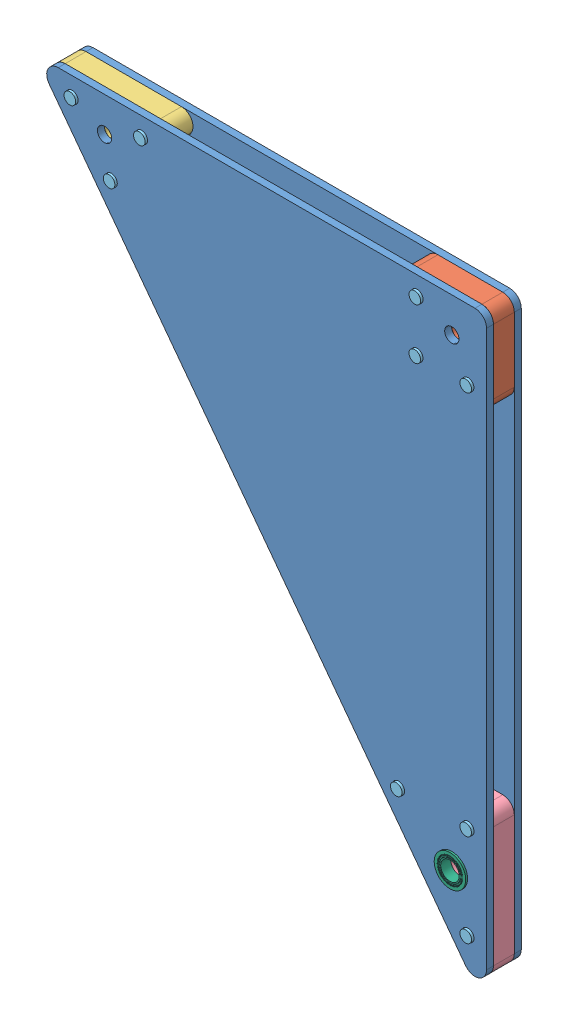
SolidWorks assembly 上方三脚架装配, configuration 默认. Lengths in mm.
Overall size (190 250 18.2).
16 component instances, 6 part files, 34 mates.
Components (placement in the parent):
- 上方三角架-1: 上方三角架 [默认] at (15.576 92.6021 249) size (190 250 3)
- 上方三角架打印连接件1-1: 上方三角架打印连接件1 [默认] at (9.4062 87.7623 261) x (-1 0 0) z (0 0 -1) size (38 38 9)
- 上方三角架打印连接件2-1: 上方三角架打印连接件2 [默认] at (-158.621 80.2816 261) x (-1 0 0) z (0 0 -1) size (51.2 41.04 9)
- 上方三角架打印连接件3-1: 上方三角架打印连接件3 [默认] at (10.8476 -100.5584 261) x (-1 0 0) z (0 0 -1) size (49 62 9)
- 上方三角架-2: 上方三角架 [默认] at (15.576 92.6021 261) size (190 250 3)
- flat head rivets gb-1: flat head rivets gb [GB_CONNECTING_PIECE_RIVET_FHRS 5X16] at (0.576 99.6021 246.8) x (0 0 1) z (-1 0 0) size (18.2 10.29 10.29)
- flat head rivets gb-2: flat head rivets gb [GB_CONNECTING_PIECE_RIVET_FHRS 5X16] at (0.576 77.6021 246.8) x (0 0 1) z (-0.08667 -0.996237 0) size (18.2 10.29 10.29)
- flat head rivets gb-3: flat head rivets gb [GB_CONNECTING_PIECE_RIVET_FHRS 5X16] at (22.576 77.6021 246.8) x (0 0 1) z (-0.981467 0.191632 0) size (18.2 10.29 10.29)
- flat head rivets gb-4: flat head rivets gb [GB_CONNECTING_PIECE_RIVET_FHRS 5X16] at (-118.424 99.6021 246.8) x (0 0 1) z (0.923728 0.383049 0) size (18.2 10.29 10.29)
- flat head rivets gb-5: flat head rivets gb [GB_CONNECTING_PIECE_RIVET_FHRS 5X16] at (-148.424 99.6021 246.8) x (0 0 1) z (0.923728 0.383049 0) size (18.2 10.29 10.29)
- flat head rivets gb-6: flat head rivets gb [GB_CONNECTING_PIECE_RIVET_FHRS 5X16] at (-131.4729 77.0007 246.8) x (0 0 1) z (-0.923728 -0.383049 0) size (18.2 10.29 10.29)
- flat head rivets gb-7: flat head rivets gb [GB_CONNECTING_PIECE_RIVET_FHRS 5X16] at (-7.424 -88.3979 246.8) x (0 0 1) z (0.923728 0.383049 0) size (18.2 10.29 10.29)
- flat head rivets gb-8: flat head rivets gb [GB_CONNECTING_PIECE_RIVET_FHRS 5X16] at (22.576 -88.3979 246.8) x (0 0 1) z (-0.990291 -0.139007 0) size (18.2 10.29 10.29)
- flat head rivets gb-9: flat head rivets gb [GB_CONNECTING_PIECE_RIVET_FHRS 5X16] at (22.576 -128.3979 246.8) x (0 0 1) z (-0.99385 -0.110732 0) size (18.2 10.29 10.29)
- SFL678ZZ深沟球法兰杯轴承-1: SFL678ZZ深沟球法兰杯轴承 [默认] at (15.576 -107.3979 262.6) x (0 0 1) z (-0.7065 0.707713 0) size (4.3 13.6 13.6)
- SFL678ZZ深沟球法兰杯轴承-2: SFL678ZZ深沟球法兰杯轴承 [默认] at (15.576 -107.3979 250.4) x (0 0 -1) z (0.871739 0.48997 0) size (4.3 13.6 13.6)
Mates (geometry in assembly coordinates):
- 同心1: concentric: cylinder of 上方三角架-1 through (15.576 -107.3979 252) axis (0 0 -1) radius 6.05; cylinder of 上方三角架打印连接件3-1 through (15.576 -107.3979 252) axis (0 0 1) radius 6
- 重合1: coincident: cylinder of 上方三角架-1 through (-7.424 -88.3979 252) axis (0 0 -1) radius 2.6; circle of 上方三角架打印连接件3-1
- 重合2: coincident: plane of 上方三角架-1 through (15.576 92.6021 252) normal (0 0 1); plane of 上方三角架打印连接件3-1 through (10.8476 -100.5584 252) normal (0 0 -1)
- 同心2: concentric: cylinder of 上方三角架-1 through (15.576 92.6021 252) axis (0 0 -1) radius 3.1; cylinder of 上方三角架打印连接件1-1 through (15.576 92.6021 252) axis (0 0 1) radius 3.05
- 重合3: coincident: plane of 上方三角架-1 through (15.576 92.6021 252) normal (0 0 1); plane of 上方三角架打印连接件1-1 through (9.4062 87.7623 252) normal (0 0 -1)
- 同心3: concentric: cylinder of 上方三角架-1 through (22.576 77.6021 252) axis (0 0 -1) radius 2.55; cylinder of 上方三角架打印连接件1-1 through (22.576 77.6021 252) axis (0 0 1) radius 2.5
- 同心4: concentric: cylinder of 上方三角架-1 through (-134.424 92.6021 252) axis (0 0 -1) radius 3.1; cylinder of 上方三角架打印连接件2-1 through (-134.424 92.6021 252) axis (0 0 1) radius 3.05
- 重合5: coincident: plane of 上方三角架-1 through (15.576 92.6021 252) normal (0 0 1); plane of 上方三角架打印连接件2-1 through (-158.621 80.2816 252) normal (0 0 -1)
- 同心7: concentric: cylinder of 上方三角架-1 through (-118.424 99.6021 252) axis (0 0 -1) radius 2.55; cylinder of 上方三角架打印连接件2-1 through (-118.424 99.6021 252) axis (0 0 1) radius 2.55
- 重合7: coincident: plane of 上方三角架打印连接件1-1 through (9.4062 87.7623 261) normal (0 0 1); plane of 上方三角架-2 through (15.576 92.6021 261) normal (0 0 -1)
- 同心8: concentric: cylinder of 上方三角架打印连接件1-1 through (15.576 92.6021 252) axis (0 0 1) radius 3.05; cylinder of 上方三角架-2 through (15.576 92.6021 264) axis (0 0 -1) radius 3.1
- 同心9: concentric: cylinder of 上方三角架打印连接件2-1 through (-134.424 92.6021 252) axis (0 0 1) radius 3.05; cylinder of 上方三角架-2 through (-134.424 92.6021 264) axis (0 0 -1) radius 3.1
- 同心10: concentric: cylinder of 上方三角架打印连接件1-1 through (0.576 99.6021 252) axis (0 0 1) radius 2.5; cylinder of flat head rivets gb-1 through (0.576 99.6021 244.4817) axis (0 0 -1) radius 2.5
- 重合9: coincident: plane of 上方三角架-1 through (15.576 92.6021 249) normal (0 0 -1); plane of flat head rivets gb-1 through (0.576 104.6281 249) normal (0 0 1)
- 同心11: concentric: cylinder of 上方三角架打印连接件1-1 through (0.576 77.6021 252) axis (0 0 1) radius 2.5; cylinder of flat head rivets gb-2 through (0.576 77.6021 244.4817) axis (0 0 -1) radius 2.5
- 重合10: coincident: plane of 上方三角架-1 through (15.576 92.6021 249) normal (0 0 -1); plane of flat head rivets gb-2 through (-4.4311 78.0377 249) normal (0 0 1)
- 同心12: concentric: cylinder of 上方三角架打印连接件1-1 through (22.576 77.6021 252) axis (0 0 1) radius 2.5; cylinder of flat head rivets gb-3 through (22.576 77.6021 244.4817) axis (0 0 -1) radius 2.5
- 重合11: coincident: plane of 上方三角架-1 through (15.576 92.6021 249) normal (0 0 -1); plane of flat head rivets gb-3 through (23.5392 82.535 249) normal (0 0 1)
- 同心13: concentric: cylinder of 上方三角架-1 through (-118.424 99.6021 252) axis (0 0 -1) radius 2.55; cylinder of flat head rivets gb-4 through (-118.424 99.6021 244.4817) axis (0 0 -1) radius 2.5
- 重合12: coincident: plane of 上方三角架-1 through (15.576 92.6021 249) normal (0 0 -1); plane of flat head rivets gb-4 through (-116.4988 94.9594 249) normal (0 0 1)
- 同心14: concentric: cylinder of 上方三角架-1 through (-148.424 99.6021 252) axis (0 0 -1) radius 2.55; cylinder of flat head rivets gb-5 through (-148.424 99.6021 244.4817) axis (0 0 -1) radius 2.5
- 重合13: coincident: plane of 上方三角架-1 through (15.576 92.6021 249) normal (0 0 -1); plane of flat head rivets gb-5 through (-146.4988 94.9594 249) normal (0 0 1)
- 同心15: concentric: cylinder of 上方三角架-1 through (-131.4729 77.0007 252) axis (0 0 -1) radius 2.55; cylinder of flat head rivets gb-6 through (-131.4729 77.0007 244.4817) axis (0 0 -1) radius 2.5
- 重合14: coincident: plane of 上方三角架-1 through (15.576 92.6021 249) normal (0 0 -1); circle of flat head rivets gb-6
- 同心16: concentric: cylinder of 上方三角架-1 through (-7.424 -88.3979 252) axis (0 0 -1) radius 2.6; cylinder of flat head rivets gb-7 through (-7.424 -88.3979 244.4817) axis (0 0 -1) radius 2.5
- 重合15: coincident: plane of 上方三角架-1 through (15.576 92.6021 249) normal (0 0 -1); plane of flat head rivets gb-7 through (-5.4988 -93.0406 249) normal (0 0 1)
- 同心17: concentric: circle of 上方三角架-1; cylinder of flat head rivets gb-8 through (22.576 -88.3979 244.4817) axis (0 0 -1) radius 2.5
- 重合16: coincident: plane of 上方三角架-1 through (15.576 92.6021 249) normal (0 0 -1); plane of flat head rivets gb-8 through (21.8774 -83.4207 249) normal (0 0 1)
- 同心18: concentric: cylinder of 上方三角架-1 through (22.576 -128.3979 252) axis (0 0 -1) radius 2.6; cylinder of flat head rivets gb-9 through (22.576 -128.3979 244.4817) axis (0 0 -1) radius 2.5
- 重合17: coincident: plane of 上方三角架-1 through (15.576 92.6021 249) normal (0 0 -1); plane of flat head rivets gb-9 through (22.0195 -123.4028 249) normal (0 0 1)
- 同心19: concentric: cylinder of 上方三角架打印连接件3-1 through (15.576 -107.3979 252) axis (0 0 1) radius 6; cylinder of SFL678ZZ深沟球法兰杯轴承-1 through (15.576 -107.3979 255.6875) axis (0 0 -1) radius 6
- 重合18: coincident: plane of 上方三角架-2 through (15.576 92.6021 264) normal (0 0 1); plane of SFL678ZZ深沟球法兰杯轴承-1 through (20.3885 -102.5937 264) normal (0 0 -1)
- 同心20: concentric: cylinder of 上方三角架打印连接件3-1 through (15.576 -107.3979 252) axis (0 0 1) radius 6; cylinder of SFL678ZZ深沟球法兰杯轴承-2 through (15.576 -107.3979 257.3125) axis (0 0 1) radius 6
- 重合19: coincident: plane of 上方三角架-1 through (15.576 92.6021 249) normal (0 0 -1); circle of SFL678ZZ深沟球法兰杯轴承-2
